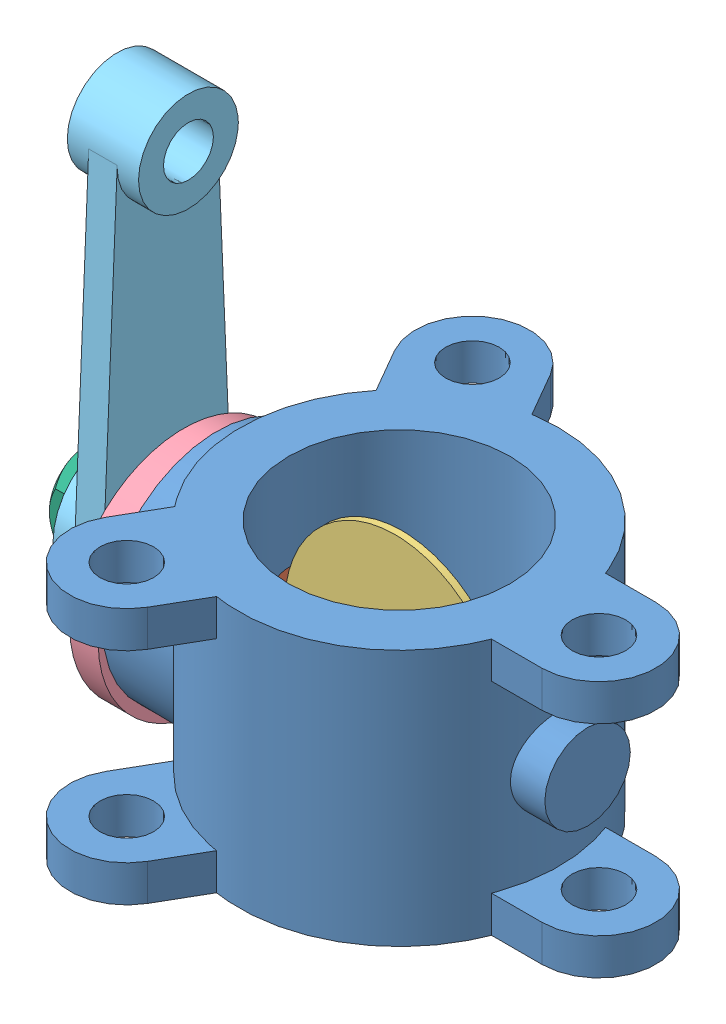
SolidWorks assembly Assem1, configuration Default. Lengths in mm.
Overall size (504.8 483.09 403.11).
9 component instances, 7 part files, 15 mates.
Components (placement in the parent):
- Body-1: Body [Default] at (175.3565 213.0693 294.4504) size (385 225 403.11)
- Shaft-1: Shaft [Default] at (329.3565 213.0693 294.4504) x (0 0 1) z (-1 0 0) size (87.2 87.2 433.8)
- Plate-1: Plate [Default] at (174.4565 213.0693 291.3504) x (1 0 0) z (0 -1 0) size (193.8 6 205)
- Retainer-1: Retainer [Default] at (-9.6435 204.7886 298.5726) x (0 -0.920988 0.389591) z (0 0.389591 0.920988) size (200 25 200)
- Arm-1: Arm [Default] at (-40.8935 213.0693 294.4504) x (0 1 0) z (0 0 -1) size (400 62.5 112.5)
- Nut-1: Nut [Default] at (-72.1435 213.0693 294.4504) x (0 1 0) z (0 0 1) size (87.63 25 69)
- Bolt-1: Bolt [Default] at (28.3565 159.5783 358.4143) x (0 0.034122 -0.999418) z (0 0.999418 0.034122) size (30 52.87 30)
- Bolt-2: Bolt [Default] at (28.3565 279.2182 307.805) x (0 -0.882582 0.470159) z (0 -0.470159 -0.882582) size (30 52.87 30)
- Bolt-3: Bolt [Default] at (28.3565 175.5693 229.4985) x (0 0.84846 0.529259) z (0 -0.529259 0.84846) size (30 52.87 30)
Mates (geometry in assembly coordinates):
- Concentric1: concentric aligned: cylinder of Body-1 through (-499824.6435 213.0693 294.4504) axis (1 0 0) radius 37.5; cylinder of Shaft-1 through (329.3565 213.0693 294.4504) axis (1 0 0) radius 28
- Coincident1: coincident aligned: plane of Body-1 through (15.3565 213.0693 294.4504) normal (-1 0 0); plane of Shaft-1 through (15.3565 213.0693 338.0504) normal (-1 0 0)
- Coincident2: coincident anti-aligned: plane of Shaft-1 through (271.3565 169.4693 291.3504) normal (0 0 1); plane of Plate-1 through (174.4565 213.0693 291.3504) normal (0 0 -1)
- Coincident3: coincident anti-aligned: circle of Shaft-1; cylinder of Plate-1 through (224.4565 213.0693 297.3504) axis (0 0 -1) radius 6.25
- Coincident4: coincident anti-aligned: circle of Shaft-1; cylinder of Plate-1 through (124.4565 213.0693 297.3504) axis (0 0 -1) radius 6.25
- Tangent4: tangent aligned: cylinder of Retainer-1 through (15.3565 204.7886 298.5726) axis (-1 0 0) radius 28; cylinder of Shaft-1 through (329.3565 213.0693 294.4504) axis (1 0 0) radius 18.75
- Concentric3: concentric aligned: cylinder of Body-1 through (28.3565 175.5693 229.4985) axis (-1 0 0) radius 10.15; cylinder of Retainer-1 through (15.3565 175.5693 229.4985) axis (-1 0 0) radius 10.15
- Coincident5: coincident anti-aligned: plane of Body-1 through (15.3565 213.0693 294.4504) normal (-1 0 0); plane of Retainer-1 through (15.3565 204.7886 298.5726) normal (1 0 0)
- Concentric4: concentric anti-aligned: cylinder of Shaft-1 through (329.3565 213.0693 294.4504) axis (1 0 0) radius 18.75; cylinder of Arm-1 through (-9.6435 213.0693 294.4504) axis (-1 0 0) radius 28.15
- Coincident6: coincident anti-aligned: plane of Shaft-1 through (-72.1435 248.0693 288.1504) normal (0 1 0); plane of Arm-1 through (-9.6435 248.0693 300.7504) normal (0 -1 0)
- Coincident7: coincident anti-aligned: plane of Retainer-1 through (-9.6435 204.7886 298.5726) normal (-1 0 0); plane of Arm-1 through (-9.6435 213.0693 294.4504) normal (1 0 0)
- Concentric6: concentric anti-aligned: cylinder of Shaft-1 through (329.3565 213.0693 294.4504) axis (1 0 0) radius 18.75; cylinder of Nut-1 through (-72.1435 213.0693 294.4504) axis (-1 0 0) radius 18.5
- Coincident8: coincident anti-aligned: plane of Arm-1 through (-72.1435 213.0693 294.4504) normal (-1 0 0); plane of Nut-1 through (-72.1435 213.0693 294.4504) normal (1 0 0)
- Concentric7: concentric anti-aligned: cylinder of Retainer-1 through (15.3565 159.5783 358.4143) axis (-1 0 0) radius 10.15; cylinder of Bolt-1 through (-9.6435 159.5783 358.4143) axis (1 0 0) radius 10
- Coincident9: coincident anti-aligned: plane of Retainer-1 through (-9.6435 204.7886 298.5726) normal (-1 0 0); plane of Bolt-1 through (-9.6435 159.5783 358.4143) normal (1 0 0)
